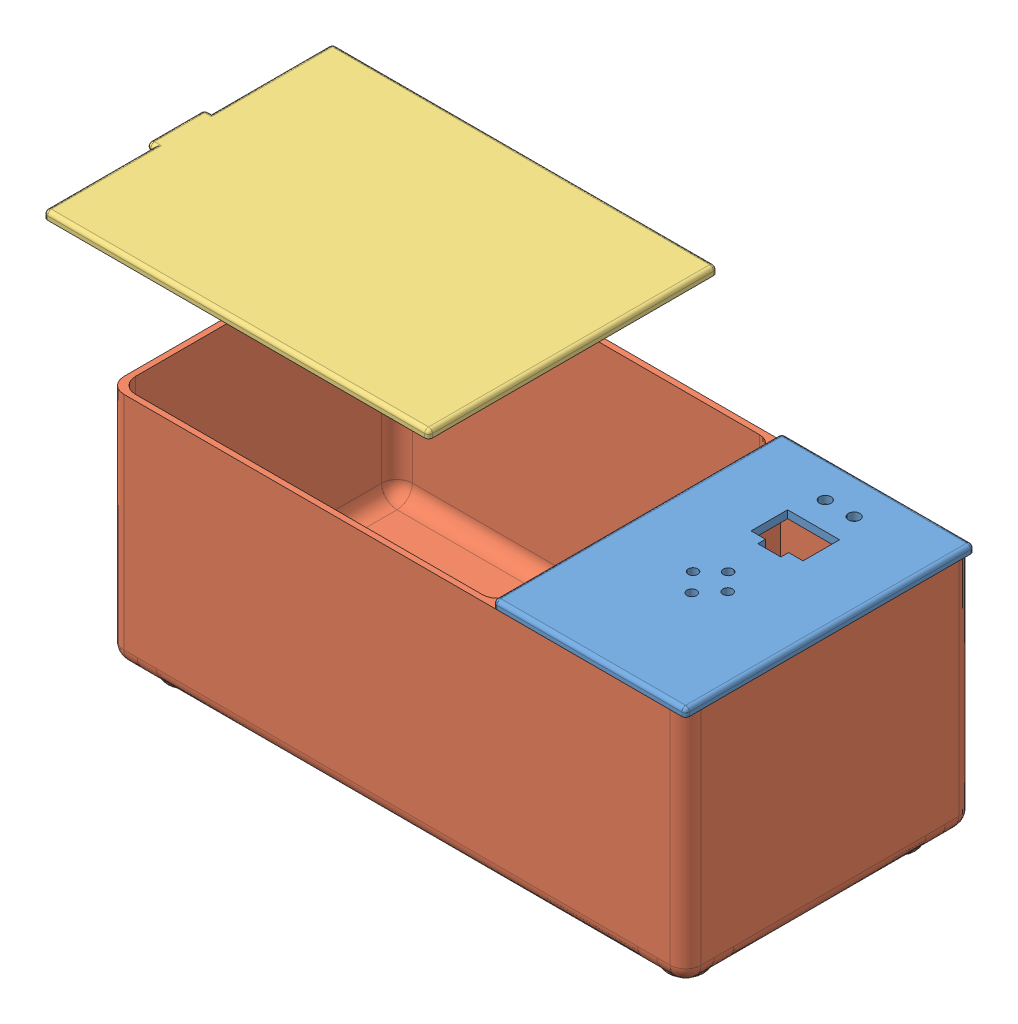
SolidWorks assembly Ass02, configuration Default. Lengths in mm.
Overall size (310.09 220.56 177.05).
3 component instances, 3 part files, 3 mates.
Components (placement in the parent):
- displaypart-1: displaypart [Default] at (-10.7264 74.4543 152.9416) size (100 4 150)
- enclosure-1: enclosure [Default] at (-210.7264 -48.5457 152.9416) size (300 131 150)
- top slider-4: top slider [Default] at (-223.684 160.0188 85.2778) x (-1 0 0) z (0 0 -1) size (203.54 4 150)
Mates (geometry in assembly coordinates):
- Coincident1: coincident aligned: line of displaypart-1 through (-8.7264 74.4543 152.9416) axis (1 0 0); line of enclosure-1 through (-202.7264 74.4543 152.9416) axis (1 0 0)
- Parallel1: parallel aligned: line of displaypart-1 through (89.2736 74.4543 150.9416) axis (0 0 -1); line of enclosure-1 through (89.2736 74.4543 144.9416) axis (0 0 -1)
- Coincident5: coincident aligned: line of displaypart-1 through (89.2736 74.4543 150.9416) axis (0 0 -1); line of enclosure-1 through (89.2736 74.4543 144.9416) axis (0 0 -1)
